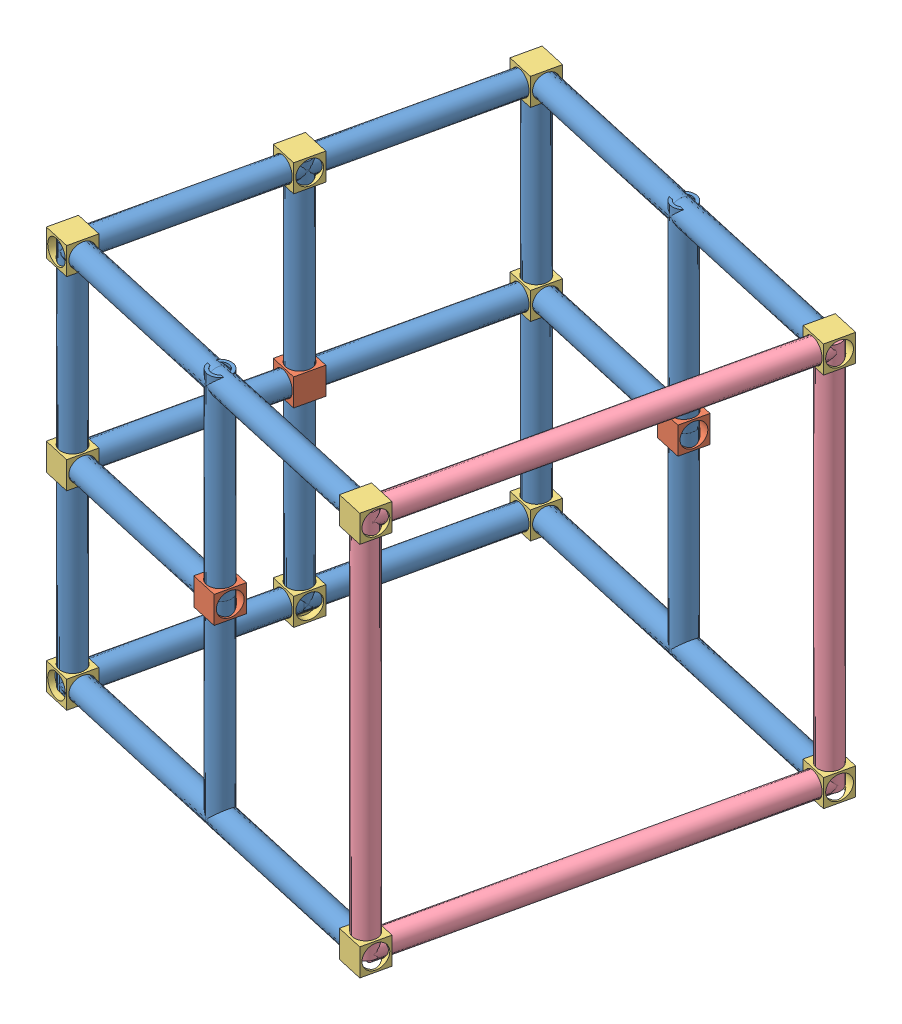
SolidWorks assembly _base, configuration Default. Lengths in mm.
Overall size (585.44 479.99 584.17).
45 component instances, 4 part files, 82 mates.
Components (placement in the parent):
- 9inPVC-1: 9inPVC [Default] at (68.2891 -2.5751 -3.3804) x (0.973326 -0.067249 0.219348) z (-0.219845 0 0.975535) size (26.67 26.67 228.6)
- 9inPVC-2: 9inPVC [Default] at (-32.2242 -2.5751 442.6341) x (-0.641309 0.753548 -0.144525) z (0.219845 0 -0.975535) size (26.67 26.67 228.6)
- 9inPVC-3: 9inPVC [Default] at (18.7665 225.6879 216.3694) x (-0.596193 0 0.802841) z (0 -1 0) size (26.67 26.67 228.6)
- 9inPVC-4: 9inPVC [Default] at (18.7665 -231.5121 216.3694) x (-0.368817 0 -0.929502) z (0 1 0) size (26.67 26.67 228.6)
- 9inPVC-5: 9inPVC [Default] at (69.2382 215.874 -7.5918) x (0.475995 0.872882 0.10727) z (-0.219845 0 0.975535) size (26.67 26.67 228.6)
- middleConnectorPieceNew-1: middleConnectorPieceNew [Default] at (18.7665 -18.4501 216.3694) x (-0.219845 0 0.975535) z (-0.975535 0 -0.219845) size (31.75 31.75 31.75)
- 9inPVC-6: 9inPVC [Default] at (18.9815 215.874 215.4154) x (0.73224 -0.660753 0.165017) z (-0.219845 0 0.975535) size (26.67 26.67 228.6)
- rightAngle-3: rightAngle [Default] at (54.5744 -2.5751 -14.7331) x (0.219845 0 -0.975535) z (0 -1 0) size (31.75 31.75 31.75)
- rightAngle-4: rightAngle [Default] at (3.2799 215.874 212.8793) x (0 1 0) z (0.219845 0 -0.975535) size (31.75 31.75 31.75)
- rightAngle-5: rightAngle [Default] at (70.061 231.749 -11.2431) x (0.219845 0 -0.975535) z (-0.975535 0 -0.219845) size (31.75 31.75 31.75)
- rightAngle-6: rightAngle [Default] at (3.2799 -226.488 212.8793) x (0 -1 0) z (-0.219845 0 0.975535) size (31.75 31.75 31.75)
- 9inPVC-7: 9inPVC [Default] at (68.1507 -226.488 -2.7663) x (0.945181 0.247512 0.213005) z (-0.219845 0 0.975535) size (26.67 26.67 228.6)
- 9inPVC-8: 9inPVC [Default] at (17.894 -226.488 220.2409) x (0.635482 -0.758718 0.143211) z (-0.219845 0 0.975535) size (26.67 26.67 228.6)
- 9inPVC-9: 9inPVC [Default] at (70.061 -235.6043 -11.2431) x (0.282586 0 -0.959242) z (0 1 0) size (26.67 26.67 228.6)
- 9inPVC-10: 9inPVC [Default] at (70.061 221.5957 -11.2431) x (0.490055 0 -0.871691) z (0 -1 0) size (26.67 26.67 228.6)
- rightAngle-7: rightAngle [Default] at (73.551 -226.488 -26.7297) x (0 -1 0) z (-0.975535 0 -0.219845) size (31.75 31.75 31.75)
- rightAngle-8: rightAngle [Default] at (-30.3986 -242.363 434.533) x (-0.975535 0 -0.219845) z (0.219845 0 -0.975535) size (31.75 31.75 31.75)
- rightAngle-9: rightAngle [Default] at (-33.8886 -2.5751 450.0196) x (-0.975535 0 -0.219845) z (0 -1 0) size (31.75 31.75 31.75)
- rightAngle-10: rightAngle [Default] at (-30.3986 231.749 434.533) x (-0.975535 0 -0.219845) z (-0.219845 0 0.975535) size (31.75 31.75 31.75)
- 9inPVC-11: 9inPVC [Default] at (-30.3986 -4.8289 434.533) x (0.91731 0 0.398174) z (0 -1 0) size (26.67 26.67 228.6)
- 9inPVC-12: 9inPVC [Default] at (-30.3986 223.7711 434.533) x (0.985071 0 -0.172149) z (0 -1 0) size (26.67 26.67 228.6)
- 9inPVC-13: 9inPVC [Default] at (-31.104 -2.5751 434.374) x (0.219845 0 -0.975535) z (0.975535 0 0.219845) size (26.67 26.67 228.6)
- 9inPVC-14: 9inPVC [Default] at (-31.104 -226.488 434.374) x (0.219845 0 -0.975535) z (0.975535 0 0.219845) size (26.67 26.67 228.6)
- 9inPVC-15: 9inPVC [Default] at (-31.104 215.874 434.374) x (0.219845 0 -0.975535) z (0.975535 0 0.219845) size (26.67 26.67 228.6)
- 9inPVC-16: 9inPVC [Default] at (69.3556 -226.488 -11.402) x (-0.06795 0.951036 0.301518) z (0.975535 0 0.219845) size (26.67 26.67 228.6)
- 9inPVC-17: 9inPVC [Default] at (69.3556 -2.5751 -11.402) x (-0.043947 0.979816 0.195011) z (0.975535 0 0.219845) size (26.67 26.67 228.6)
- 9inPVC-18: 9inPVC [Default] at (69.3556 215.874 -11.402) x (0.0121 -0.998484 -0.053694) z (0.975535 0 0.219845) size (26.67 26.67 228.6)
- 9inPVC-20: 9inPVC [Default] at (191.9032 -226.488 484.6307) x (-0.202967 -0.384255 0.90064) z (0.975535 0 0.219845) size (26.67 26.67 228.6)
- 9inPVC-22: 9inPVC [Default] at (191.9032 215.874 484.6307) x (-0.210605 0.28687 0.934533) z (0.975535 0 0.219845) size (26.67 26.67 228.6)
- 9inPVC-23: 9inPVC [Default] at (292.3628 -226.488 38.8546) x (-0.217894 0.132948 0.966875) z (0.975535 0 0.219845) size (26.67 26.67 228.6)
- 9inPVC-24: 9inPVC [Default] at (292.3628 215.874 38.8546) x (-0.009639 0.999038 0.04277) z (0.975535 0 0.219845) size (26.67 26.67 228.6)
- middleConnectorPieceNew-2: middleConnectorPieceNew [Default] at (193.8268 -18.4501 485.0642) x (-0.975535 0 -0.219845) z (0.219845 0 -0.975535) size (31.75 31.75 31.75)
- middleConnectorPieceNew-3: middleConnectorPieceNew [Default] at (294.2864 13.2999 39.2881) x (-0.975535 0 -0.219845) z (-0.219845 0 0.975535) size (31.75 31.75 31.75)
- 9inPVC-25: 9inPVC [Default] at (193.8268 228.3297 485.0642) x (-0.974818 0 0.223003) z (0 -1 0) size (26.67 26.67 228.6)
- 9inPVC-26: 9inPVC [Default] at (294.2864 227.0896 39.2881) x (-0.975615 0 0.219489) z (0 -1 0) size (26.67 26.67 228.6)
- 9inPVC-27: 9inPVC [Default] at (294.2864 -230.1104 39.2881) x (0.615465 0 0.788164) z (0 1 0) size (26.67 26.67 228.6)
- 9inPVC-28: 9inPVC [Default] at (193.8268 -228.8703 485.0642) x (-0.347589 0 0.937647) z (0 1 0) size (26.67 26.67 228.6)
- 18inPVC-1: 18inPVC [Default] at (515.7262 -226.488 89.3252) x (0.929394 0.303905 0.209447) z (-0.219845 0 0.975535) size (26.67 26.67 457.2)
- rightAngle-12: rightAngle [Default] at (411.8052 -226.488 550.4607) x (0 1 0) z (-0.975535 0 -0.219845) size (31.75 31.75 31.75)
- rightAngle-13: rightAngle [Default] at (411.8052 215.874 550.4607) x (0 1 0) z (-0.975535 0 -0.219845) size (31.75 31.75 31.75)
- 18inPVC-2: 18inPVC [Default] at (515.4791 215.874 90.4215) x (0.972657 -0.07676 0.219197) z (-0.219845 0 0.975535) size (26.67 26.67 457.2)
- rightAngle-14: rightAngle [Default] at (515.7548 -210.613 89.198) x (0.219845 0 -0.975535) z (-0.975535 0 -0.219845) size (31.75 31.75 31.75)
- rightAngle-15: rightAngle [Default] at (515.7548 231.749 89.198) x (0.219845 0 -0.975535) z (-0.975535 0 -0.219845) size (31.75 31.75 31.75)
- 18inPVC-3: 18inPVC [Default] at (415.2952 225.8875 534.9741) x (0.471481 0 0.881876) z (0 -1 0) size (26.67 26.67 457.2)
- 18inPVC-4: 18inPVC [Default] at (515.7548 224.1658 89.198) x (0.705495 0 0.708715) z (0 -1 0) size (26.67 26.67 457.2)
Mates (geometry in assembly coordinates):
- Concentric1: concentric anti-aligned: circle of middleConnectorPiece-1; cylinder of 9inPVC-2 through (18.0324 -2.5751 219.6268) axis (-0.219845 0 0.975535) radius 13.335
- Concentric2: concentric anti-aligned: cylinder of 9inPVC-1 through (18.0324 -2.5751 219.6268) axis (0.219845 0 -0.975535) radius 13.335; circle of middleConnectorPiece-1
- Coincident1: coincident anti-aligned: plane of 9inPVC-1 through (18.0324 -2.5751 219.6268) normal (-0.219845 0 0.975535); plane of 9inPVC-2 through (18.0324 -2.5751 219.6268) normal (0.219845 0 -0.975535)
- Concentric5: concentric anti-aligned: circle of middleConnectorPieceNew-1; cylinder of 9inPVC-3 through (18.7665 -2.9121 216.3694) axis (0 1 0) radius 13.335
- Concentric6: concentric anti-aligned: circle of middleConnectorPieceNew-1; cylinder of 9inPVC-4 through (18.7665 -2.9121 216.3694) axis (0 -1 0) radius 13.335
- Coincident2: coincident anti-aligned: plane of 9inPVC-3 through (18.7665 -2.9121 216.3694) normal (0 -1 0); plane of 9inPVC-4 through (18.7665 -2.9121 216.3694) normal (0 1 0)
- Concentric7: concentric anti-aligned: cylinder of 9inPVC-1 through (18.0324 -2.5751 219.6268) axis (0.219845 0 -0.975535) radius 13.335; circle of rightAngle-3
- Concentric8: concentric anti-aligned: cylinder of 9inPVC-3 through (18.7665 -2.9121 216.3694) axis (0 1 0) radius 13.335; circle of rightAngle-4
- Parallel3: parallel aligned: plane of middleConnectorPieceNew-1 through (37.7432 13.2999 204.3728) normal (0.975535 0 0.219845); plane of rightAngle-4 through (34.2531 215.874 219.8594) normal (0.975535 0 0.219845)
- Concentric11: concentric aligned: cylinder of rightAngle-4 through (15.2765 215.874 231.856) axis (0.219845 0 -0.975535) radius 13.716; cylinder of 9inPVC-5 through (18.9815 215.874 215.4154) axis (0.219845 0 -0.975535) radius 13.335
- Concentric12: concentric aligned: cylinder of 9inPVC-5 through (18.9815 215.874 215.4154) axis (0.219845 0 -0.975535) radius 13.335; cylinder of 9inPVC-6 through (-31.2752 215.874 438.4226) axis (0.219845 0 -0.975535) radius 13.335
- Coincident5: coincident anti-aligned: plane of 9inPVC-5 through (18.9815 215.874 215.4154) normal (-0.219845 0 0.975535); plane of 9inPVC-6 through (18.9815 215.874 215.4154) normal (0.219845 0 -0.975535)
- Concentric14: concentric anti-aligned: cylinder of 9inPVC-5 through (18.9815 215.874 215.4154) axis (0.219845 0 -0.975535) radius 13.335; cylinder of rightAngle-5 through (68.665 215.874 -5.0484) axis (-0.219845 0 0.975535) radius 13.716
- Concentric16: concentric: cylinder of 9inPVC-4 through (18.7665 -2.9121 216.3694) axis (0 -1 0) radius 13.335; circle of rightAngle-6
- Parallel5: parallel aligned: plane of middleConnectorPieceNew-1 through (37.7432 13.2999 204.3728) normal (0.975535 0 0.219845); plane of rightAngle-6 through (34.2531 -226.488 219.8594) normal (0.975535 0 0.219845)
- Concentric17: concentric anti-aligned: circle of rightAngle-6; cylinder of 9inPVC-7 through (17.894 -226.488 220.2409) axis (0.219845 0 -0.975535) radius 13.335
- Concentric18: concentric aligned: circle of rightAngle-6; cylinder of 9inPVC-8 through (-32.3626 -226.488 443.2481) axis (0.219845 0 -0.975535) radius 13.335
- Coincident9: coincident anti-aligned: plane of 9inPVC-7 through (17.894 -226.488 220.2409) normal (-0.219845 0 0.975535); plane of 9inPVC-8 through (17.894 -226.488 220.2409) normal (0.219845 0 -0.975535)
- Concentric19: concentric aligned: circle of rightAngle-3; circle of rightAngle-5
- Parallel6: parallel aligned: plane of middleConnectorPieceNew-1 through (37.7432 13.2999 204.3728) normal (0.975535 0 0.219845); plane of rightAngle-3 through (85.5476 -2.5751 -7.753) normal (0.975535 0 0.219845)
- Concentric20: concentric anti-aligned: cylinder of 9inPVC-9 through (70.061 -7.0043 -11.2431) axis (0 -1 0) radius 13.335; cylinder of 9inPVC-10 through (70.061 -7.0043 -11.2431) axis (0 1 0) radius 13.335
- Coincident13: coincident anti-aligned: plane of 9inPVC-9 through (70.061 -7.0043 -11.2431) normal (0 1 0); plane of 9inPVC-10 through (70.061 -7.0043 -11.2431) normal (0 -1 0)
- Concentric21: concentric aligned: circle of rightAngle-3; cylinder of 9inPVC-9 through (70.061 -7.0043 -11.2431) axis (0 -1 0) radius 13.335
- Parallel7: parallel aligned: plane of rightAngle-3 through (85.5476 -2.5751 -7.753) normal (0.975535 0 0.219845); plane of rightAngle-7 through (82.0576 -210.613 7.7336) normal (0.975535 0 0.219845)
- Concentric22: concentric anti-aligned: cylinder of 9inPVC-7 through (17.894 -226.488 220.2409) axis (0.219845 0 -0.975535) radius 9.525; cylinder of rightAngle-7 through (68.2462 -226.488 -3.19) axis (-0.219845 0 0.975535) radius 13.716
- Concentric23: concentric anti-aligned: cylinder of 9inPVC-9 through (70.061 -7.0043 -11.2431) axis (0 -1 0) radius 13.335; circle of rightAngle-7
- Concentric24: concentric anti-aligned: cylinder of 9inPVC-6 through (-31.2752 215.874 438.4226) axis (0.219845 0 -0.975535) radius 13.335; circle of rightAngle-10
- Parallel8: parallel aligned: plane of middleConnectorPieceNew-1 through (37.7432 13.2999 204.3728) normal (0.975535 0 0.219845); plane of rightAngle-10 through (-18.402 199.999 453.5097) normal (0.975535 0 0.219845)
- Concentric25: concentric anti-aligned: cylinder of 9inPVC-2 through (18.0324 -2.5751 219.6268) axis (-0.219845 0 0.975535) radius 13.335; circle of rightAngle-9
- Parallel9: parallel aligned: plane of middleConnectorPieceNew-1 through (37.7432 13.2999 204.3728) normal (0.975535 0 0.219845); plane of rightAngle-9 through (-11.4219 -18.4501 422.5364) normal (0.975535 0 0.219845)
- Concentric26: concentric anti-aligned: cylinder of 9inPVC-8 through (-32.3626 -226.488 443.2481) axis (0.219845 0 -0.975535) radius 13.335; circle of rightAngle-8
- Parallel11: parallel aligned: plane of middleConnectorPieceNew-1 through (37.7432 13.2999 204.3728) normal (0.975535 0 0.219845); plane of rightAngle-8 through (-11.4219 -210.613 422.5364) normal (0.975535 0 0.219845)
- Concentric27: concentric anti-aligned: circle of rightAngle-8; circle of rightAngle-9
- Concentric28: concentric anti-aligned: circle of rightAngle-9; circle of rightAngle-10
- Concentric29: concentric aligned: cylinder of 9inPVC-11 through (-30.3986 -233.4289 434.533) axis (0 1 0) radius 13.335; cylinder of 9inPVC-12 through (-30.3986 -4.8289 434.533) axis (0 1 0) radius 13.335
- Coincident20: coincident anti-aligned: plane of 9inPVC-11 through (-30.3986 -4.8289 434.533) normal (0 1 0); plane of 9inPVC-12 through (-30.3986 -4.8289 434.533) normal (0 -1 0)
- Concentric30: concentric anti-aligned: circle of rightAngle-9; cylinder of 9inPVC-11 through (-30.3986 -233.4289 434.533) axis (0 1 0) radius 13.335
- Concentric31: concentric anti-aligned: circle of rightAngle-9; cylinder of 9inPVC-13 through (191.9032 -2.5751 484.6307) axis (-0.975535 0 -0.219845) radius 13.335
- Concentric32: concentric anti-aligned: circle of rightAngle-8; cylinder of 9inPVC-14 through (191.9032 -226.488 484.6307) axis (-0.975535 0 -0.219845) radius 13.335
- Concentric33: concentric anti-aligned: circle of rightAngle-10; cylinder of 9inPVC-15 through (191.9032 215.874 484.6307) axis (-0.975535 0 -0.219845) radius 13.335
- Concentric34: concentric aligned: circle of rightAngle-7; cylinder of 9inPVC-16 through (292.3628 -226.488 38.8546) axis (-0.975535 0 -0.219845) radius 13.335
- Concentric35: concentric anti-aligned: circle of rightAngle-3; cylinder of 9inPVC-17 through (292.3628 -2.5751 38.8546) axis (-0.975535 0 -0.219845) radius 13.335
- Concentric38: concentric aligned: cylinder of 9inPVC-18 through (292.3628 215.874 38.8546) axis (-0.975535 0 -0.219845) radius 13.335; circle of rightAngle-5
- Parallel12: parallel aligned: plane of 9inPVC-18 through (292.3628 215.874 38.8546) normal (0.975535 0 0.219845); plane of 9inPVC-17 through (292.3628 -2.5751 38.8546) normal (0.975535 0 0.219845)
- Coincident21: coincident aligned: plane of 9inPVC-17 through (292.3628 -2.5751 38.8546) normal (0.975535 0 0.219845); plane of 9inPVC-16 through (292.3628 -226.488 38.8546) normal (0.975535 0 0.219845)
- Coincident22: coincident aligned: plane of 9inPVC-18 through (292.3628 215.874 38.8546) normal (0.975535 0 0.219845); plane of 9inPVC-17 through (292.3628 -2.5751 38.8546) normal (0.975535 0 0.219845)
- Coincident23: coincident aligned: plane of 9inPVC-14 through (191.9032 -226.488 484.6307) normal (0.975535 0 0.219845); plane of 9inPVC-13 through (191.9032 -2.5751 484.6307) normal (0.975535 0 0.219845)
- Coincident24: coincident aligned: plane of 9inPVC-15 through (191.9032 215.874 484.6307) normal (0.975535 0 0.219845); plane of 9inPVC-13 through (191.9032 -2.5751 484.6307) normal (0.975535 0 0.219845)
- Coincident25: coincident aligned: plane of 9inPVC-14 through (191.9032 -226.488 484.6307) normal (0.975535 0 0.219845); plane of 9inPVC-16 through (292.3628 -226.488 38.8546) normal (0.975535 0 0.219845)
- Concentric39: concentric aligned: cylinder of 9inPVC-18 through (292.3628 215.874 38.8546) axis (-0.975535 0 -0.219845) radius 9.525; cylinder of 9inPVC-24 through (515.3701 215.874 89.1113) axis (-0.975535 0 -0.219845) radius 9.525
- Parallel13: parallel aligned: cylinder of 9inPVC-15 through (191.9032 215.874 484.6307) axis (-0.975535 0 -0.219845) radius 13.335; cylinder of 9inPVC-16 through (292.3628 -226.488 38.8546) axis (-0.975535 0 -0.219845) radius 13.335
- Concentric42: concentric aligned: cylinder of 9inPVC-15 through (191.9032 215.874 484.6307) axis (-0.975535 0 -0.219845) radius 13.335; cylinder of 9inPVC-22 through (414.9105 215.874 534.8873) axis (-0.975535 0 -0.219845) radius 13.335
- Concentric43: concentric aligned: cylinder of 9inPVC-16 through (292.3628 -226.488 38.8546) axis (-0.975535 0 -0.219845) radius 13.335; cylinder of 9inPVC-23 through (515.3701 -226.488 89.1113) axis (-0.975535 0 -0.219845) radius 13.335
- Concentric45: concentric aligned: cylinder of 9inPVC-14 through (191.9032 -226.488 484.6307) axis (-0.975535 0 -0.219845) radius 13.335; cylinder of 9inPVC-20 through (414.9105 -226.488 534.8873) axis (-0.975535 0 -0.219845) radius 13.335
- Coincident27: coincident anti-aligned: plane of 9inPVC-16 through (292.3628 -226.488 38.8546) normal (0.975535 0 0.219845); plane of 9inPVC-23 through (292.3628 -226.488 38.8546) normal (-0.975535 0 -0.219845)
- Coincident29: coincident anti-aligned: plane of 9inPVC-18 through (292.3628 215.874 38.8546) normal (0.975535 0 0.219845); plane of 9inPVC-24 through (292.3628 215.874 38.8546) normal (-0.975535 0 -0.219845)
- Coincident30: coincident anti-aligned: circle of 9inPVC-15; plane of 9inPVC-22 through (191.9032 215.874 484.6307) normal (-0.975535 0 -0.219845)
- Coincident32: coincident anti-aligned: circle of 9inPVC-14; plane of 9inPVC-20 through (191.9032 -226.488 484.6307) normal (-0.975535 0 -0.219845)
- Parallel14: parallel aligned: plane of rightAngle-9 through (-33.8886 -2.5751 450.0196) normal (-0.219845 0 0.975535); plane of middleConnectorPieceNew-2 through (205.8234 13.2999 504.0408) normal (-0.219845 0 0.975535)
- Concentric47: concentric aligned: cylinder of 9inPVC-17 through (292.3628 -2.5751 38.8546) axis (-0.975535 0 -0.219845) radius 13.335; circle of middleConnectorPieceNew-3
- Parallel15: parallel aligned: plane of rightAngle-3 through (89.0377 -18.4501 -23.2396) normal (0.219845 0 -0.975535); plane of middleConnectorPieceNew-3 through (313.263 -18.4501 27.2915) normal (0.219845 0 -0.975535)
- Parallel16: parallel aligned: plane of middleConnectorPieceNew-2 through (212.8035 13.2999 473.0676) normal (0.975535 0 0.219845); plane of middleConnectorPieceNew-3 through (306.283 -18.4501 58.2648) normal (0.975535 0 0.219845)
- Coincident36: coincident aligned: plane of middleConnectorPieceNew-2 through (212.8035 13.2999 473.0676) normal (0.975535 0 0.219845); plane of middleConnectorPieceNew-3 through (306.283 -18.4501 58.2648) normal (0.975535 0 0.219845)
- Concentric48: concentric anti-aligned: circle of middleConnectorPieceNew-3; cylinder of 9inPVC-27 through (294.2864 -1.5104 39.2881) axis (0 -1 0) radius 13.335
- Concentric49: concentric anti-aligned: cylinder of 9inPVC-26 through (294.2864 -1.5104 39.2881) axis (0 1 0) radius 13.335; cylinder of 9inPVC-27 through (294.2864 -1.5104 39.2881) axis (0 -1 0) radius 13.335
- Concentric50: concentric anti-aligned: circle of middleConnectorPieceNew-2; cylinder of 9inPVC-28 through (193.8268 -0.2703 485.0642) axis (0 -1 0) radius 13.335
- Concentric51: concentric anti-aligned: cylinder of 9inPVC-25 through (193.8268 -0.2703 485.0642) axis (0 1 0) radius 13.335; cylinder of 9inPVC-28 through (193.8268 -0.2703 485.0642) axis (0 -1 0) radius 13.335
- Coincident37: coincident anti-aligned: plane of 9inPVC-25 through (193.8268 -0.2703 485.0642) normal (0 -1 0); plane of 9inPVC-28 through (193.8268 -0.2703 485.0642) normal (0 1 0)
- Coincident38: coincident anti-aligned: plane of 9inPVC-26 through (294.2864 -1.5104 39.2881) normal (0 -1 0); plane of 9inPVC-27 through (294.2864 -1.5104 39.2881) normal (0 1 0)
- Concentric52: concentric anti-aligned: cylinder of 9inPVC-20 through (414.9105 -226.488 534.8873) axis (-0.975535 0 -0.219845) radius 13.335; circle of rightAngle-12
- Parallel17: parallel aligned: plane of rightAngle-8 through (-18.402 -210.613 453.5097) normal (-0.219845 0 0.975535); plane of rightAngle-12 through (411.8052 -226.488 550.4607) normal (-0.219845 0 0.975535)
- Concentric53: concentric aligned: cylinder of 18inPVC-1 through (415.2128 -226.488 535.3397) axis (0.219845 0 -0.975535) radius 13.335; circle of rightAngle-12
- Concentric54: concentric aligned: cylinder of 9inPVC-22 through (414.9105 215.874 534.8873) axis (-0.975535 0 -0.219845) radius 13.335; circle of rightAngle-13
- Parallel18: parallel aligned: plane of rightAngle-12 through (411.8052 -226.488 550.4607) normal (-0.219845 0 0.975535); plane of rightAngle-13 through (411.8052 215.874 550.4607) normal (-0.219845 0 0.975535)
- Coincident43: coincident aligned: plane of rightAngle-12 through (434.2719 -242.363 522.9775) normal (0.975535 0 0.219845); plane of rightAngle-13 through (434.2719 199.999 522.9775) normal (0.975535 0 0.219845)
- Concentric55: concentric aligned: circle of rightAngle-13; cylinder of 18inPVC-2 through (414.9658 215.874 536.436) axis (0.219845 0 -0.975535) radius 13.335
- Concentric56: concentric anti-aligned: cylinder of 9inPVC-24 through (515.3701 215.874 89.1113) axis (-0.975535 0 -0.219845) radius 13.335; circle of rightAngle-15
- Concentric57: concentric anti-aligned: cylinder of 18inPVC-2 through (414.9658 215.874 536.436) axis (0.219845 0 -0.975535) radius 13.335; circle of rightAngle-15
- Concentric58: concentric anti-aligned: cylinder of 9inPVC-23 through (515.3701 -226.488 89.1113) axis (-0.975535 0 -0.219845) radius 13.335; circle of rightAngle-14
- Concentric59: concentric anti-aligned: cylinder of 18inPVC-1 through (415.2128 -226.488 535.3397) axis (0.219845 0 -0.975535) radius 13.335; cylinder of rightAngle-14 through (514.3588 -226.488 95.3926) axis (-0.219845 0 0.975535) radius 13.716
- Concentric60: concentric anti-aligned: circle of rightAngle-15; cylinder of 18inPVC-4 through (515.7548 -233.0342 89.198) axis (0 1 0) radius 13.335
- Concentric61: concentric anti-aligned: circle of rightAngle-13; cylinder of 18inPVC-3 through (415.2952 -231.3125 534.9741) axis (0 1 0) radius 13.335
